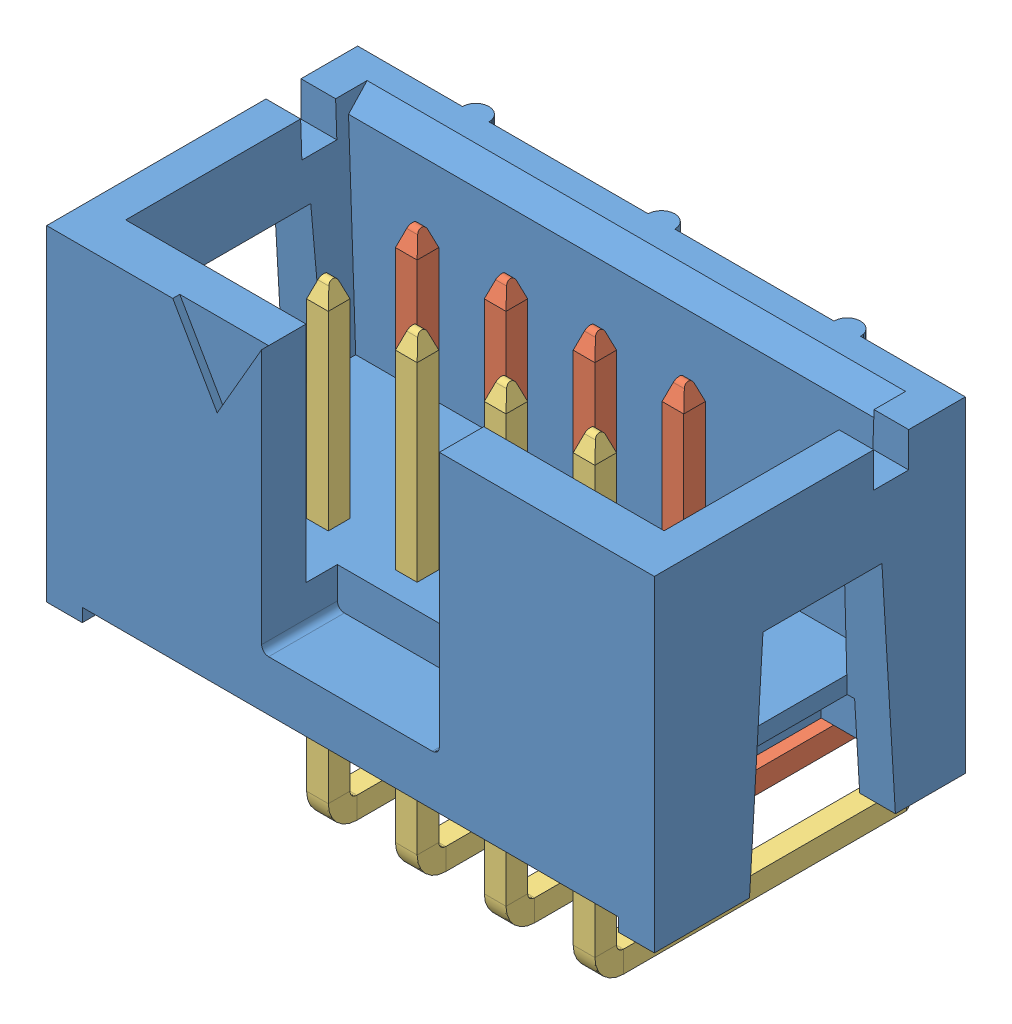
SolidWorks assembly Connector, Header IDC, 8 Position, Right Angle, Shrouded, 75867_y32_asm, configuration Default. Lengths in mm.
Overall size (17.37 13.97 12.34).
10 component instances, 3 part files, 0 mates.
Components (placement in the parent):
- 75867_y32_asm.stp-1: 75867_y32_asm.stp [Default] at origin size (17.37 13.97 12.34)
  - 71965_Y08.stp-1: 71965_Y08.stp [Default] at (2.0715 -6.0403 -4.4148) size (17.37 9.32 9.27)
  - 71953_X03.stp-1: 71953_X03.stp [Default] at (9.4865 -7.8403 -7.8656) x (0 -1 0) z (0 0 1) size (11.03 0.62 6.94)
  - 71953_X03.stp-2: 71953_X03.stp [Default] at (12.0265 -7.8403 -7.8656) x (0 -1 0) z (0 0 1) size (11.03 0.62 6.94)
  - 71953_X03.stp-3: 71953_X03.stp [Default] at (14.5665 -7.8403 -7.8656) x (0 -1 0) z (0 0 1) size (11.03 0.62 6.94)
  - 71953_X03.stp-4: 71953_X03.stp [Default] at (17.1065 -7.8403 -7.8656) x (0 -1 0) z (0 0 1) size (11.03 0.62 6.94)
  - 71953_X04.stp-1: 71953_X04.stp [Default] at (9.4865 -10.3803 -7.8656) x (0 -1 0) z (0 0 1) size (13.57 0.62 9.48)
  - 71953_X04.stp-2: 71953_X04.stp [Default] at (12.0265 -10.3803 -7.8656) x (0 -1 0) z (0 0 1) size (13.57 0.62 9.48)
  - 71953_X04.stp-3: 71953_X04.stp [Default] at (14.5665 -10.3803 -7.8656) x (0 -1 0) z (0 0 1) size (13.57 0.62 9.48)
  - 71953_X04.stp-4: 71953_X04.stp [Default] at (17.1065 -10.3803 -7.8656) x (0 -1 0) z (0 0 1) size (13.57 0.62 9.48)
